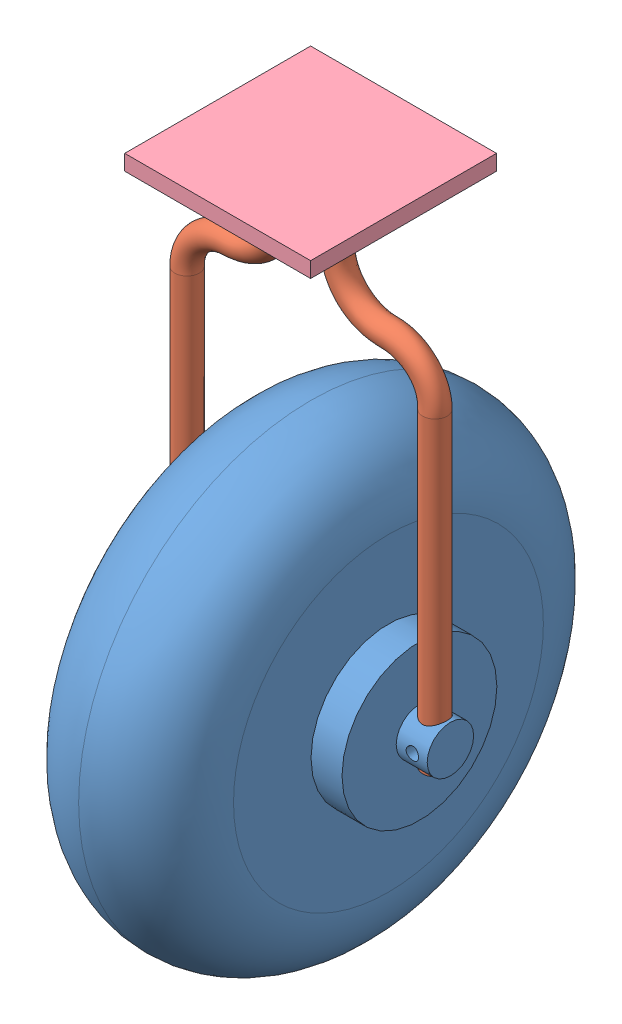
SolidWorks assembly Montaj2, configuration Varsayılan. Lengths in mm.
Overall size (45 109.55 75).
6 component instances, 4 part files, 12 mates.
Components (placement in the parent):
- teker-1: teker [Varsayılan] at (-96.4188 18.2391 16.1212) size (45 75 75)
- tekertutacağı-1: tekertutacağı [Varsayılan] at (-95.165 -24.524 16.138) x (-0.00479 0 -0.999989) z (0.999989 0 -0.00479) size (4.12 72.8 19.37)
- tekertutacağı-2: tekertutacağı [Varsayılan] at (-47.6741 -24.5106 16.0152) x (0.0286 0 0.999591) z (-0.999591 0 0.0286) size (4.12 72.8 19.37)
- tekermenteşe-1: tekermenteşe [Varsayılan] at (-66.7729 80.5024 16.5594) x (0 0 1) z (-1 0 0) size (11.94 4.5 4.93)
- tekermenteşe-2: tekermenteşe [Varsayılan] at (-76.0587 80.5345 16.0473) x (0 0 -1) z (1 0 0) size (11.94 4.5 4.93)
- sapbağlantı-2: sapbağlantı [Varsayılan] at (-71.4165 76.9961 16.185) x (0 0 -1) z (1 0 0) size (30 7.5 30)
Mates (geometry in assembly coordinates):
- Eş Merkezli8: concentric: cylinder of teker-1 through (-91.4188 23.2391 16.1212) axis (0 -1 0) radius 2; cylinder of tekertutacağı-1 through (-91.4188 64.4891 16.1212) axis (0 -1 0) radius 1.975
- Teğet6: tangent: cylinder of teker-1 through (-91.501 18.2391 21.1212) axis (0 0 -1) radius 1; cylinder of tekertutacağı-1 through (-91.4428 18.2391 11.1212) axis (0.00479 0 0.999989) radius 1
- Kilitle1: lock: unknown of teker-1; unknown of tekertutacağı-1
- Eş Merkezli25: concentric: cylinder of teker-1 through (-51.4188 23.2391 16.1212) axis (0 -1 0) radius 2; cylinder of tekertutacağı-2 through (-51.4188 64.5025 16.1212) axis (0 -1 0) radius 1.975
- Kilitle3: lock: unknown of teker-1; unknown of tekertutacağı-2
- Eş Merkezli30: concentric: circle of tekertutacağı-2; circle of tekermenteşe-1
- Paralel11: parallel: plane of tekertutacağı-2 through (-66.7143 87.2979 16.5588) normal (0 1 0); plane of tekermenteşe-1 through (-67.6997 87.2524 13.6) normal (0 1 0)
- Eş Merkezli31: concentric: circle of tekertutacağı-1; circle of tekermenteşe-2
- Paralel13: parallel: line of tekermenteşe-1 through (-68.6851 87.2524 10.5888) axis (0 0 1); line of tekermenteşe-2 through (-74.1473 87.2845 13.1805) axis (0 0 -1)
- Çakışık7: coincident: circle of tekermenteşe-2; circle of sapbağlantı-2
- Kilitle4: lock: unknown of tekertutacağı-1; unknown of sapbağlantı-2
- Kilitle6: lock: unknown of tekertutacağı-2; unknown of tekermenteşe-1
